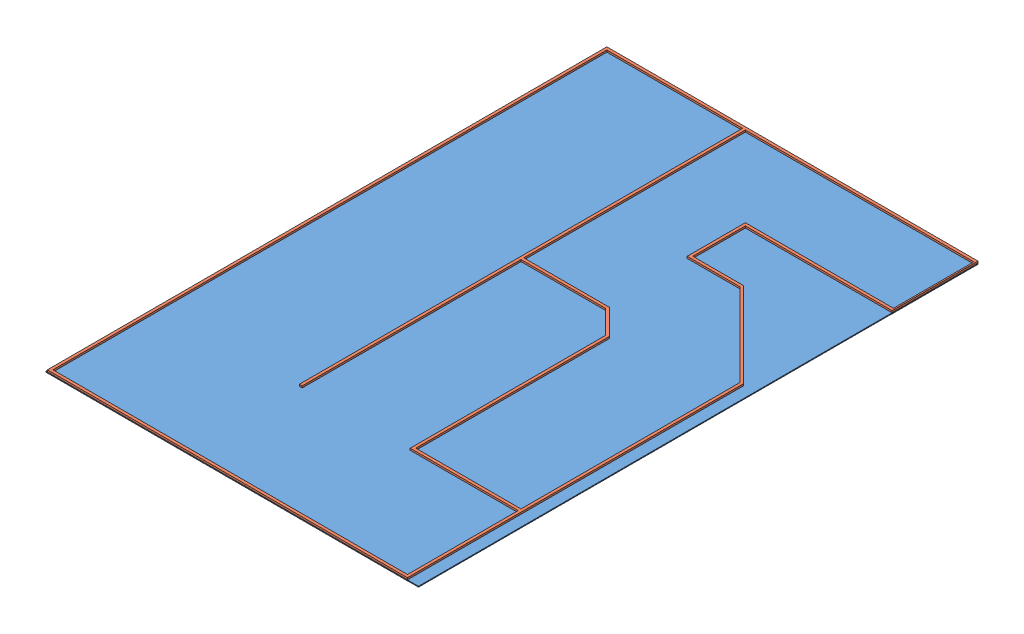
SolidWorks assembly Assem1, configuration Default. Lengths in mm.
Overall size (6725 50.8 10100).
2 component instances, 2 part files, 2 mates.
Components (placement in the parent):
- PLY-1: PLY [Default] at (3518.3065 5260.452 7892.4451) size (6725 15 10100)
- Fence-1: Fence [Default] at (3493.3065 5243.2507 11062.9596) size (6700 50.8 10100)
Mates (geometry in assembly coordinates):
- Coincident1: coincident: plane of assembly; plane of assembly; plane of PLY-1 through (-3206.6935 5245.452 12942.4451) normal (0 0 1); plane of Fence-1 through (3493.3065 5294.0507 12942.4451) normal (0 0 1)
- Coincident2: coincident: plane of assembly; plane of assembly; plane of Fence-1 through (3518.3065 5294.0507 11062.9596) normal (1 0 0); plane of PLY-1 through (3518.3065 5245.452 2842.4451) normal (1 0 0)
